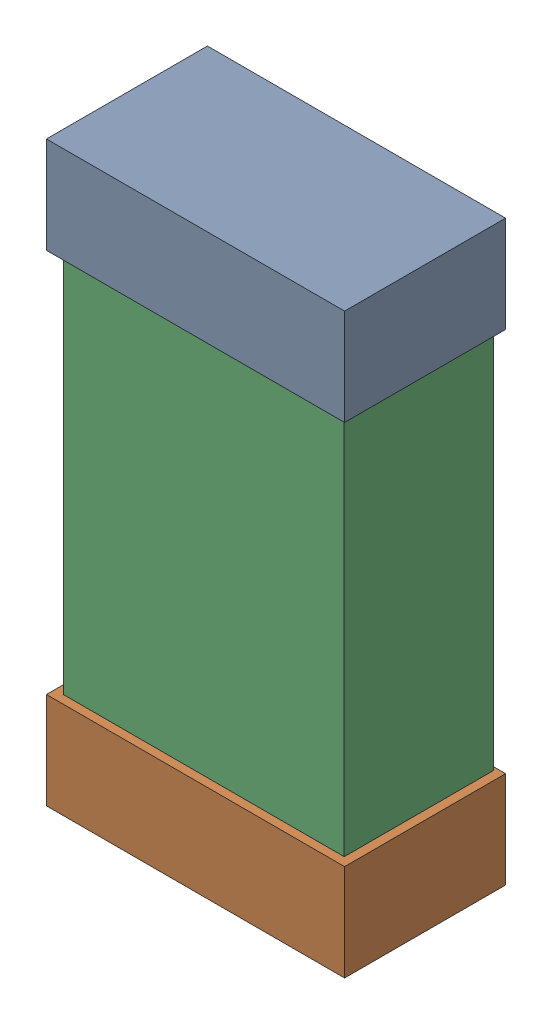
SolidWorks assembly C33, configuration Default. Lengths in mm.
Overall size (0.85 1.65 0.46).
6 component instances, 2 part files, 0 mates.
Components (placement in the parent):
- 432138512_56-1: 432138512_56 [Default] at (15.4501 59.2538 -0.8715) size (0.85 0.28 0.46)
  - Extruded-1: Extruded [Default] at origin size (0.85 0.28 0.46)
- 432138512_57-1: 432138512_57 [Default] at (15.4501 57.8822 -0.8715) size (0.85 0.28 0.46)
  - Extruded-1: Extruded [Default] at origin size (0.85 0.28 0.46)
- 432124816_28-1: 432124816_28 [Default] at (15.4501 58.568 -0.8615) size (0.8 1.5 0.42)
  - Extruded (1)-1: Extruded (1) [Default] at origin size (0.8 1.5 0.42)
